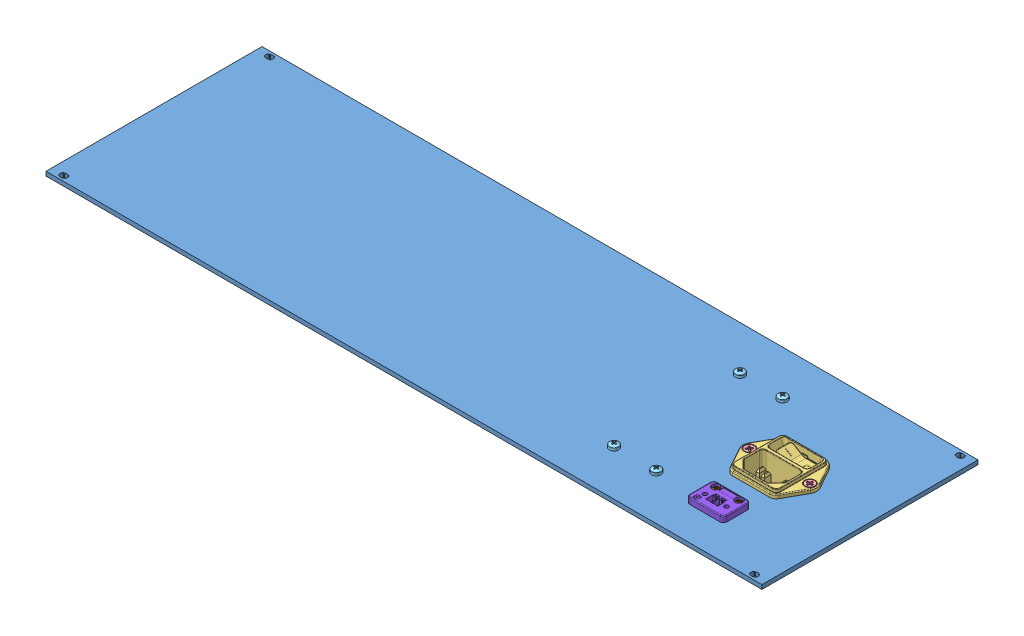
SolidWorks assembly MLA-0387-M9, configuration Default. Lengths in mm.
Overall size (426.52 36.95 128.7).
31 component instances, 14 part files, 51 mates.
Components (placement in the parent):
- MLA-0387-M8-1: MLA-0387-M8 [Default] at (14.077 -174.6299 585.4715) size (426.52 2.5 128.7)
- ECL15US12-S-1: ECL15US12-S [Default] at (340.987 202.9701 302.5215) x (0 0 -1) z (1 0 0) size (84 26.49 34.5)
- DC11_0001_001-1: DC11_0001_001 [Default] at (389.437 205.4701 308.5715) x (1 0 0) z (0 1 0) size (44 34 36.95)
- SCREW_ISO 7046-1: SCREW_ISO 7046 [VIJAK M 3x 10] at (371.437 207.6701 302.5215) x (0 -1 0) z (-0.609119 0 0.793079) size (10 5.6 5.6)
- SCREW_ISO 7046-2: SCREW_ISO 7046 [VIJAK M 3x 10] at (407.437 207.6701 302.5215) x (0 -1 0) z (0 0 1) size (10 5.6 5.6)
- M3 X 10mm Screw-1: M3 X 10mm Screw [Default] at (328.287 207.8701 340.0215) x (0 -1 0) z (0 0 1) size (12.61 5.6 5.6)
- M3 X 10mm Screw-2: M3 X 10mm Screw [Default] at (353.687 207.8701 340.2611) x (0 -1 0) z (0 0 1) size (12.61 5.6 5.6)
- M3 X 10mm Screw-3: M3 X 10mm Screw [Default] at (353.687 207.8701 265.0215) x (0 -1 0) z (0 0 1) size (12.61 5.6 5.6)
- M3 X 10mm Screw-4: M3 X 10mm Screw [Default] at (328.287 207.8701 265.0215) x (0 -1 0) z (0 0 1) size (12.61 5.6 5.6)
- M3 screw size FLAT WASHER-1: M3 screw size FLAT WASHER [Default] at (407.437 202.9701 302.5215) x (0.944963 0 -0.327176) z (0 -1 0) size (7 7 0.6)
- M3 screw size FLAT WASHER-2: M3 screw size FLAT WASHER [Default] at (371.437 202.3701 302.5215) x (1 0 0) z (0 1 0) size (7 7 0.6)
- M3 x 0.5mm Thread HEX NUT-1: M3 x 0.5mm Thread HEX NUT [Default] at (407.4348 201.1701 302.5562) x (1 0 0) z (0 1 0) size (5.5 6.35 2.6)
- M3 x 0.5mm Thread HEX NUT-2: M3 x 0.5mm Thread HEX NUT [Default] at (371.4463 201.1701 302.55) x (1 0 0) z (0 1 0) size (5.5 6.35 2.6)
- M3 screw size FLAT WASHER-3: M3 screw size FLAT WASHER [Default] at (353.687 199.8701 340.2611) x (1 0 0) z (0 1 0) size (7 7 0.6)
- M3 screw size FLAT WASHER-4: M3 screw size FLAT WASHER [Default] at (328.287 199.8701 340.0215) x (1 0 0) z (0 1 0) size (7 7 0.6)
- M3 screw size FLAT WASHER-5: M3 screw size FLAT WASHER [Default] at (328.287 200.4701 265.0215) x (1 0 0) z (0 -1 0) size (7 7 0.6)
- M3 screw size FLAT WASHER-6: M3 screw size FLAT WASHER [Default] at (353.687 200.4701 265.0215) x (1 0 0) z (0 -1 0) size (7 7 0.6)
- M3 x 0.5mm Thread HEX NUT-3: M3 x 0.5mm Thread HEX NUT [Default] at (328.3059 198.6701 265.0157) x (1 0 0) z (0 -1 0) size (5.5 6.35 2.6)
- M3 x 0.5mm Thread HEX NUT-4: M3 x 0.5mm Thread HEX NUT [Default] at (353.679 198.6701 264.9262) x (1 0 0) z (0 -1 0) size (5.5 6.35 2.6)
- M3 x 0.5mm Thread HEX NUT-5: M3 x 0.5mm Thread HEX NUT [Default] at (353.654 198.6701 340.285) x (1 0 0) z (0 1 0) size (5.5 6.35 2.6)
- M3 x 0.5mm Thread HEX NUT-6: M3 x 0.5mm Thread HEX NUT [Default] at (328.2745 198.6701 340.0301) x (1 0 0) z (0 1 0) size (5.5 6.35 2.6)
- 1829345_02-1: 1829345_02 [Default] at (387.527 203.3701 340.6215) x (0 1 0) z (-1 0 0) size (20.4 16.2 22.01)
- pan_head_phillip_mc_screw_m2-1: pan_head_phillip_mc_screw_m2 [Default] at (382.527 206.9701 333.6215) x (-0.384065 0 -0.923306) z (0.923306 0 -0.384065) size (4 9.78 4)
- pan_head_phillip_mc_screw_m2-2: pan_head_phillip_mc_screw_m2 [Default] at (396.337 206.9701 333.6215) x (0.556789 0 0.830654) z (-0.830654 0 0.556789) size (4 9.78 4)
- M2 washer-1: M2 washer [Default] at (396.337 202.6701 333.6215) size (5 0.3 5)
- M2 washer-2: M2 washer [Default] at (382.527 202.6701 333.6215) size (5 0.3 5)
- M2 Nut-1: M2 Nut [Default] at (396.337 201.0701 333.6215) x (1 0 0) z (0 -1 0) size (4 4.62 1.6)
- M2 Nut-2: M2 Nut [Default] at (382.527 201.0701 333.6215) x (1 0 0) z (0 -1 0) size (4 4.62 1.6)
- MLA-0387-C1-1: MLA-0387-C1 [Default] at (87.9984 232.5402 444.968)
- MLA-0387-C2-1: MLA-0387-C2 [Default] at (17.0703 214.5525 393.0741)
- MLA-0387-C6-1: MLA-0387-C6 [Default] at (131.9732 220.0042 408.8022)
Mates (geometry in assembly coordinates):
- Coincident1: coincident anti-aligned: plane of MLA-0387-M8-1 through (22.1573 202.9701 282.3956) normal (0 -1 0); plane of ECL15US12-S-1 through (358.237 202.9701 335.5215) normal (0 1 0)
- Distance1: distance = 22.35 mm aligned: line of ECL15US12-S-1 through (324.7368 202.9701 344.5215) axis (1 0 0); plane of MLA-0387-M8-1 through (443.237 202.9701 366.8715) normal (0 0 1)
- Coincident8: coincident anti-aligned: plane of MLA-0387-M8-1 through (22.1573 205.4701 282.3956) normal (0 1 0); plane of DC11_0001_001-1 through (378.437 205.4701 289.5215) normal (0 -1 0)
- Concentric2: concentric anti-aligned: cylinder of MLA-0387-M8-1 through (371.437 212.9701 302.5215) axis (0 -1 0) radius 1.8; cylinder of DC11_0001_001-1 through (371.437 207.6701 302.5215) axis (0 1 0) radius 1.6
- Concentric3: concentric anti-aligned: cylinder of MLA-0387-M8-1 through (407.437 212.9701 302.5215) axis (0 -1 0) radius 1.8; cylinder of DC11_0001_001-1 through (407.437 207.6701 302.5215) axis (0 1 0) radius 1.6
- Distance4: distance = 85 mm: line of MLA-0387-M8-1 through (443.237 202.9701 366.8715) axis (0 0 -1); line of ECL15US12-S-1 through (358.237 202.9701 343.5217) axis (0 0 -1)
- Concentric4: concentric aligned: cone of DC11_0001_001-1 through (371.437 207.4701 302.5215) axis (0 -1 0); cone of SCREW_ISO 7046-1 through (371.437 206.1701 302.5215) axis (0 -1 0)
- Coincident9: coincident aligned: plane of DC11_0001_001-1 through (378.437 207.6701 289.5215) normal (0 1 0); plane of SCREW_ISO 7046-1 through (371.437 207.6701 302.5215) normal (0 1 0)
- Concentric5: concentric aligned: cone of DC11_0001_001-1 through (407.437 207.4701 302.5215) axis (0 -1 0); cone of SCREW_ISO 7046-2 through (407.437 206.1701 302.5215) axis (0 -1 0)
- Coincident10: coincident aligned: plane of DC11_0001_001-1 through (378.437 207.6701 289.5215) normal (0 1 0); plane of SCREW_ISO 7046-2 through (407.437 207.6701 302.5215) normal (0 1 0)
- Coincident11: coincident anti-aligned: plane of MLA-0387-M8-1 through (22.1573 205.4701 282.3956) normal (0 1 0); plane of M3 X 10mm Screw-1 through (328.287 205.4701 338.5215) normal (0 -1 0)
- Concentric6: concentric aligned: cylinder of MLA-0387-M8-1 through (328.287 212.9701 340.0215) axis (0 -1 0) radius 1.8; cylinder of M3 X 10mm Screw-1 through (328.287 195.4701 340.0215) axis (0 -1 0) radius 2.8
- Coincident12: coincident anti-aligned: plane of MLA-0387-M8-1 through (22.1573 205.4701 282.3956) normal (0 1 0); plane of M3 X 10mm Screw-2 through (353.687 205.4701 338.7611) normal (0 -1 0)
- Concentric7: concentric aligned: cylinder of MLA-0387-M8-1 through (353.687 212.9701 340.2611) axis (0 -1 0) radius 1.8; cylinder of M3 X 10mm Screw-2 through (353.687 195.4701 340.2611) axis (0 -1 0) radius 2.8
- Coincident13: coincident anti-aligned: plane of MLA-0387-M8-1 through (22.1573 205.4701 282.3956) normal (0 1 0); plane of M3 X 10mm Screw-3 through (353.687 205.4701 263.5215) normal (0 -1 0)
- Concentric8: concentric aligned: cylinder of MLA-0387-M8-1 through (353.687 212.9701 265.0215) axis (0 -1 0) radius 1.8; cylinder of M3 X 10mm Screw-3 through (353.687 195.4701 265.0215) axis (0 -1 0) radius 2.8
- Coincident14: coincident anti-aligned: plane of MLA-0387-M8-1 through (22.1573 205.4701 282.3956) normal (0 1 0); plane of M3 X 10mm Screw-4 through (328.287 205.4701 263.5215) normal (0 -1 0)
- Concentric9: concentric aligned: cylinder of MLA-0387-M8-1 through (328.287 212.9701 265.0215) axis (0 -1 0) radius 1.8; cylinder of M3 X 10mm Screw-4 through (328.287 195.4701 265.0215) axis (0 -1 0) radius 2.8
- Coincident15: coincident anti-aligned: plane of MLA-0387-M8-1 through (22.1573 202.9701 282.3956) normal (0 -1 0); plane of M3 screw size FLAT WASHER-1 through (407.437 202.9701 302.5215) normal (0 1 0)
- Concentric10: concentric anti-aligned: cylinder of M3 screw size FLAT WASHER-1 through (407.437 202.3701 302.5215) axis (0 1 0) radius 1.6; cylinder of SCREW_ISO 7046-2 through (407.437 197.6701 302.5215) axis (0 -1 0) radius 2.8
- Coincident16: coincident anti-aligned: plane of MLA-0387-M8-1 through (22.1573 202.9701 282.3956) normal (0 -1 0); plane of M3 screw size FLAT WASHER-2 through (371.437 202.9701 302.5215) normal (0 1 0)
- Concentric11: concentric aligned: cylinder of MLA-0387-M8-1 through (371.437 212.9701 302.5215) axis (0 -1 0) radius 1.8; cylinder of M3 screw size FLAT WASHER-2 through (371.437 202.9701 302.5215) axis (0 -1 0) radius 1.6
- Coincident17: coincident anti-aligned: plane of M3 screw size FLAT WASHER-1 through (407.437 202.3701 302.5215) normal (0 -1 0); plane of M3 x 0.5mm Thread HEX NUT-1 through (404.6848 202.3701 300.9685) normal (0 1 0)
- Coincident18: coincident anti-aligned: plane of M3 screw size FLAT WASHER-2 through (371.437 202.3701 302.5215) normal (0 -1 0); plane of M3 x 0.5mm Thread HEX NUT-2 through (368.6963 202.3701 300.9623) normal (0 1 0)
- Coincident19: coincident anti-aligned: plane of ECL15US12-S-1 through (358.237 200.4701 335.0215) normal (0 -1 0); plane of M3 screw size FLAT WASHER-3 through (353.687 200.4701 340.2611) normal (0 1 0)
- Concentric13: concentric aligned: cylinder of M3 X 10mm Screw-2 through (353.687 195.4701 340.2611) axis (0 -1 0) radius 2.8; cylinder of M3 screw size FLAT WASHER-3 through (353.687 200.4701 340.2611) axis (0 -1 0) radius 3.5
- Coincident20: coincident anti-aligned: plane of ECL15US12-S-1 through (358.237 200.4701 335.0215) normal (0 -1 0); plane of M3 screw size FLAT WASHER-4 through (328.287 200.4701 340.0215) normal (0 1 0)
- Concentric14: concentric aligned: cylinder of M3 X 10mm Screw-1 through (328.287 195.4701 340.0215) axis (0 -1 0) radius 2.8; cylinder of M3 screw size FLAT WASHER-4 through (328.287 200.4701 340.0215) axis (0 -1 0) radius 3.5
- Coincident21: coincident anti-aligned: plane of ECL15US12-S-1 through (358.237 200.4701 270.0215) normal (0 -1 0); plane of M3 screw size FLAT WASHER-5 through (328.287 200.4701 265.0215) normal (0 1 0)
- Concentric15: concentric aligned: cylinder of M3 X 10mm Screw-4 through (328.287 195.4701 265.0215) axis (0 -1 0) radius 2.8; circle of M3 screw size FLAT WASHER-5
- Coincident22: coincident anti-aligned: plane of ECL15US12-S-1 through (358.237 200.4701 270.0215) normal (0 -1 0); plane of M3 screw size FLAT WASHER-6 through (353.687 200.4701 265.0215) normal (0 1 0)
- Concentric16: concentric anti-aligned: circle of M3 X 10mm Screw-3; cylinder of M3 screw size FLAT WASHER-6 through (353.687 199.8701 265.0215) axis (0 1 0) radius 3.5
- Coincident24: coincident anti-aligned: plane of M3 screw size FLAT WASHER-5 through (328.287 199.8701 265.0215) normal (0 -1 0); plane of M3 x 0.5mm Thread HEX NUT-3 through (325.5559 199.8701 266.6034) normal (0 1 0)
- Coincident25: coincident anti-aligned: plane of M3 screw size FLAT WASHER-6 through (353.687 199.8701 265.0215) normal (0 -1 0); plane of M3 x 0.5mm Thread HEX NUT-4 through (350.929 199.8701 266.5139) normal (0 1 0)
- Coincident26: coincident anti-aligned: plane of M3 screw size FLAT WASHER-3 through (353.687 199.8701 340.2611) normal (0 -1 0); plane of M3 x 0.5mm Thread HEX NUT-5 through (350.904 199.8701 338.6973) normal (0 1 0)
- Coincident27: coincident anti-aligned: plane of M3 screw size FLAT WASHER-4 through (328.287 199.8701 340.0215) normal (0 -1 0); plane of M3 x 0.5mm Thread HEX NUT-6 through (325.5245 199.8701 338.4424) normal (0 1 0)
- Concentric17: concentric anti-aligned: cylinder of MLA-0387-M8-1 through (382.527 212.9701 333.6215) axis (0 -1 0) radius 1.15; cylinder of 1829345_02-1 through (382.527 196.8661 333.6215) axis (0 1 0) radius 1.15
- Concentric18: concentric anti-aligned: cylinder of MLA-0387-M8-1 through (396.337 212.9701 333.6215) axis (0 -1 0) radius 1.15; cylinder of 1829345_02-1 through (396.337 196.8661 333.6215) axis (0 1 0) radius 1.15
- Coincident32: coincident anti-aligned: plane of MLA-0387-M8-1 through (22.1573 205.4701 282.3956) normal (0 1 0); plane of 1829345_02-1 through (380.432 205.4701 348.6415) normal (0 -1 0)
- Concentric19: concentric anti-aligned: cylinder of 1829345_02-1 through (382.527 196.8661 333.6215) axis (0 1 0) radius 1.15; cylinder of pan_head_phillip_mc_screw_m2-1 through (382.527 208.7551 333.6215) axis (0 -1 0) radius 2
- Coincident33: coincident anti-aligned: plane of 1829345_02-1 through (388.0071 206.9701 335.7282) normal (0 1 0); plane of pan_head_phillip_mc_screw_m2-1 through (382.527 206.9701 333.6215) normal (0 -1 0)
- Concentric20: concentric anti-aligned: cylinder of 1829345_02-1 through (396.337 196.8661 333.6215) axis (0 1 0) radius 1.15; circle of pan_head_phillip_mc_screw_m2-2
- Coincident34: coincident anti-aligned: plane of 1829345_02-1 through (388.0071 206.9701 335.7282) normal (0 1 0); plane of pan_head_phillip_mc_screw_m2-2 through (396.337 206.9701 333.6215) normal (0 -1 0)
- Coincident35: coincident anti-aligned: plane of MLA-0387-M8-1 through (22.1573 202.9701 282.3956) normal (0 -1 0); plane of M2 washer-1 through (396.337 202.9701 333.6215) normal (0 1 0)
- Concentric22: concentric anti-aligned: cylinder of MLA-0387-M8-1 through (396.337 212.9701 333.6215) axis (0 -1 0) radius 1.15; cylinder of M2 washer-1 through (396.337 202.6701 333.6215) axis (0 1 0) radius 1.1
- Coincident36: coincident anti-aligned: plane of MLA-0387-M8-1 through (22.1573 202.9701 282.3956) normal (0 -1 0); plane of M2 washer-2 through (382.527 202.9701 333.6215) normal (0 1 0)
- Concentric23: concentric anti-aligned: cylinder of MLA-0387-M8-1 through (382.527 212.9701 333.6215) axis (0 -1 0) radius 1.15; cylinder of M2 washer-2 through (382.527 202.6701 333.6215) axis (0 1 0) radius 1.1
- Coincident37: coincident: plane of M2 washer-1 through (396.337 202.6701 333.6215) normal (0 -1 0); plane of M2 Nut-1 through (400.837 202.6701 335.1747) normal (0 1 0)
- Concentric25: concentric anti-aligned: circle of M2 washer-1; circle of M2 Nut-1
- Coincident38: coincident anti-aligned: plane of M2 washer-2 through (382.527 202.6701 333.6215) normal (0 -1 0); plane of M2 Nut-2 through (382.527 202.6701 335.9309) normal (0 1 0)
- Concentric26: concentric aligned: cylinder of MLA-0387-M8-1 through (382.527 212.9701 333.6215) axis (0 -1 0) radius 1.15; circle of M2 Nut-2
